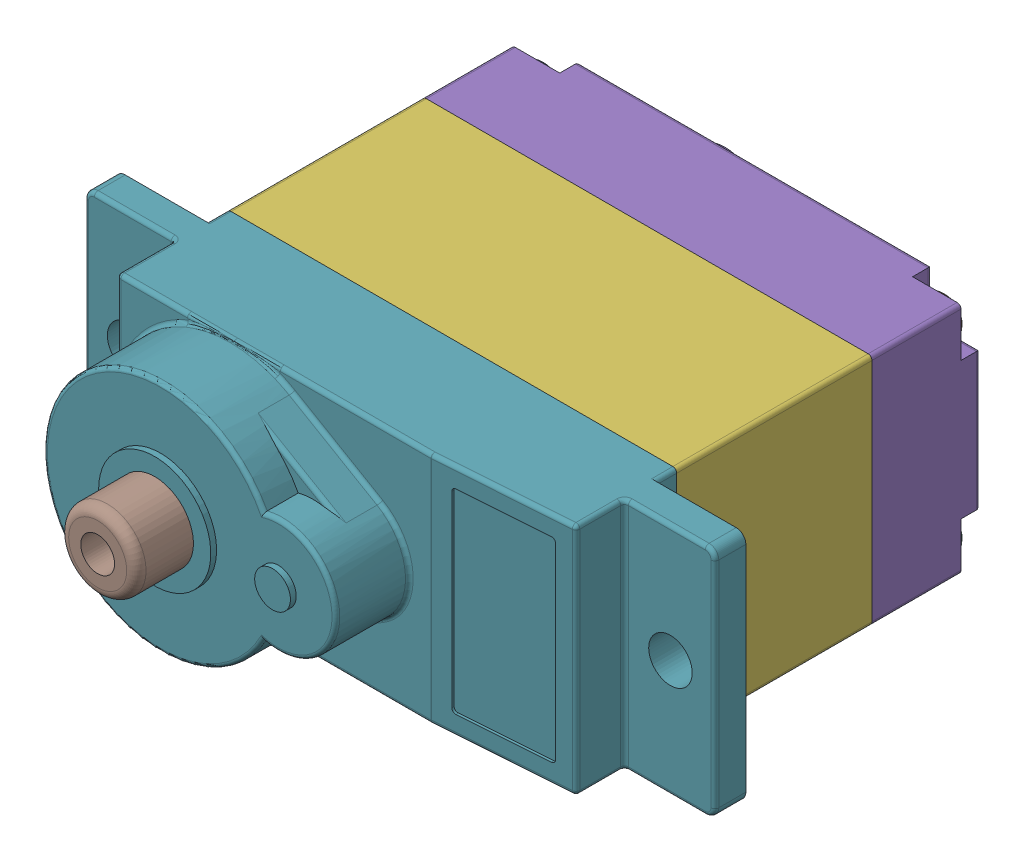
SolidWorks assembly Feetech SCS0009 v9, configuration Default. Lengths in mm.
Overall size (32.6 12.15 32.45).
6 component instances, 2 part files, 0 mates.
Components (placement in the parent):
- Feetech SCS0009-1: Feetech SCS0009 [Default] at origin size (22.81 11.66 17.77)
  - 91772A071_NO THREADS_Passivated 18-8 Stainless Steel Pan Head Phillips Screw-1: 91772A071_NO THREADS_Passivated 18-8 Stainless Steel Pan Head Phillips Screw [Default] at (-4.8 4.9736 9.9662) x (1 0 0) z (0 0 -1) size (2.06 2.06 17.77)
  - 91772A071_NO THREADS_Passivated 18-8 Stainless Steel Pan Head Phillips Screw-2: 91772A071_NO THREADS_Passivated 18-8 Stainless Steel Pan Head Phillips Screw [Default] at (15.95 4.9736 9.9662) x (1 0 0) z (0 0 -1) size (2.06 2.06 17.77)
  - 91772A071_NO THREADS_Passivated 18-8 Stainless Steel Pan Head Phillips Screw-3: 91772A071_NO THREADS_Passivated 18-8 Stainless Steel Pan Head Phillips Screw [Default] at (15.95 -4.6264 9.9662) x (1 0 0) z (0 0 -1) size (2.06 2.06 17.77)
  - 91772A071_NO THREADS_Passivated 18-8 Stainless Steel Pan Head Phillips Screw-4: 91772A071_NO THREADS_Passivated 18-8 Stainless Steel Pan Head Phillips Screw [Default] at (-4.8 -4.6264 9.9662) x (1 0 0) z (0 0 -1) size (2.06 2.06 17.77)
- eBom-FreeParts-1: eBom-FreeParts [Default] at origin size (32.6 12.15 32.45)
